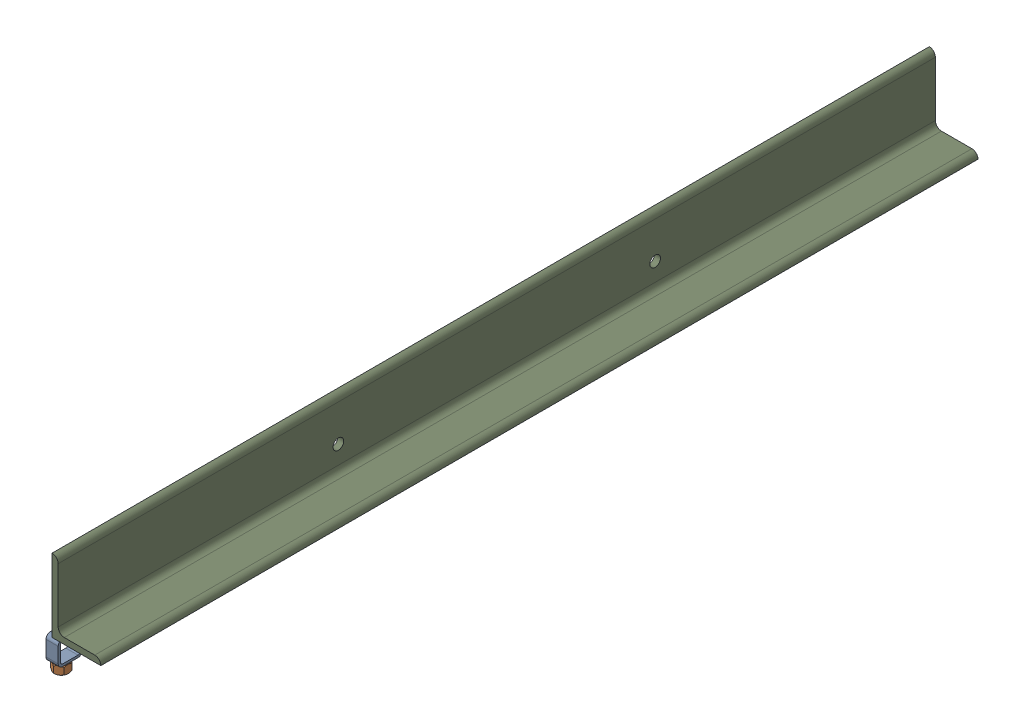
SolidWorks assembly 01-003-00-0, configuration Default. Lengths in mm.
Overall size (115.89 220.09 1828.8).
13 component instances, 3 part files, 0 mates.
Components (placement in the parent):
- 01-005-00-0-1-1: 01-005-00-0-1 [Default] at (-6.35 0 863.6) x (0 -1 0) z (-1 0 0) size (67.69 50.8 28.57)
  - tube square_ai(PreviewCfg)-1: tube square_ai(PreviewCfg) [Default] at origin size (50.8 50.8 25.4)
  - hex nut_ai(HNUT 0.7500-10-D-C)-1: hex nut_ai(HNUT 0.7500-10-D-C) [Default] at (67.691 31.75 0) x (0 0 -1) z (1 0 0) size (28.57 33 16.89)
- 01-005-00-0-2-1: 01-005-00-0-2 [Default] at (-6.35 0 -914.4) x (0 -1 0) z (-1 0 0) size (67.69 50.8 28.57)
  - tube square_ai(PreviewCfg)-1: tube square_ai(PreviewCfg) [Default] at origin size (50.8 50.8 25.4)
  - hex nut_ai(HNUT 0.7500-10-D-C)-1: hex nut_ai(HNUT 0.7500-10-D-C) [Default] at (67.691 31.75 0) x (0 0 -1) z (1 0 0) size (28.57 33 16.89)
- 01-005-00-0-3-1: 01-005-00-0-3 [Default] at (-6.35 0 -609.6) x (0 -1 0) z (-1 0 0) size (67.69 50.8 28.57)
  - tube square_ai(PreviewCfg)-1: tube square_ai(PreviewCfg) [Default] at origin size (50.8 50.8 25.4)
  - hex nut_ai(HNUT 0.7500-10-D-C)-1: hex nut_ai(HNUT 0.7500-10-D-C) [Default] at (67.691 31.75 0) x (0 0 -1) z (1 0 0) size (28.57 33 16.89)
- 01-005-00-0-4-1: 01-005-00-0-4 [Default] at (-6.35 0 558.8) x (0 -1 0) z (-1 0 0) size (67.69 50.8 28.57)
  - tube square_ai(PreviewCfg)-1: tube square_ai(PreviewCfg) [Default] at origin size (50.8 50.8 25.4)
  - hex nut_ai(HNUT 0.7500-10-D-C)-1: hex nut_ai(HNUT 0.7500-10-D-C) [Default] at (67.691 31.75 0) x (0 0 -1) z (1 0 0) size (28.57 33 16.89)
- 01-004-00-0-1: 01-004-00-0 [Default] at (-6.35 0 0) size (101.6 152.4 1828.8)
